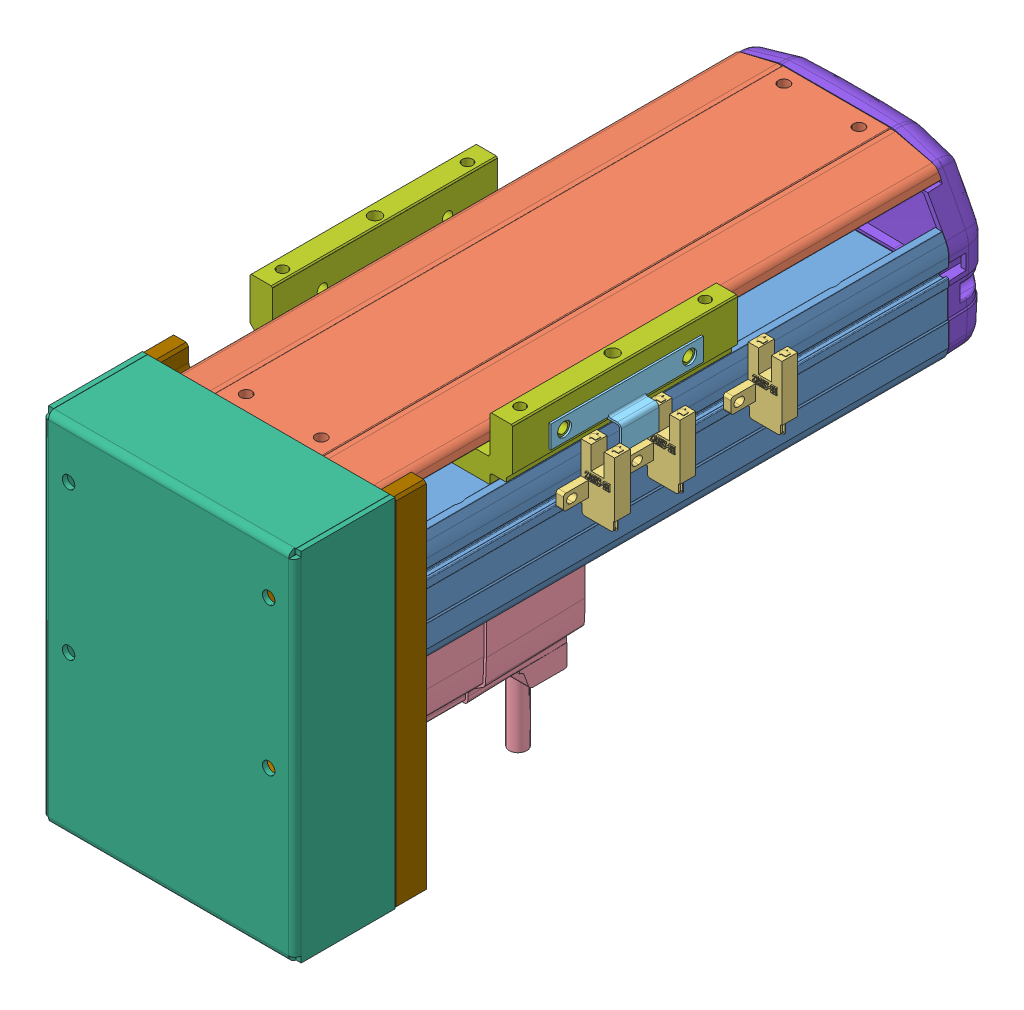
SolidWorks assembly S10-BM-100W, configuration 默认. Lengths in mm.
Overall size (117 164.58 282.34).
11 component instances, 9 part files, 37 mates.
Components (placement in the parent):
- CFS10-BR底座^CFS10-BM-100W-1: CFS10-BR底座^CFS10-BM-100W [默认] at origin size (102 43 221) (virtual)
- CFS10-BR上盖^CFS10-BM-100W-1: CFS10-BR上盖^CFS10-BM-100W [默认] at (0 59.5 119.5) size (83.88 8 227) (virtual)
-  EE-SX672 传感器^CFS10-BM-100W-1:  EE-SX672 传感器^CFS10-BM-100W [默认] at (57.75 34.1 92.3) x (1 0 0) z (0 0 -1) size (13.5 27.4 26.1) (virtual)
- M10^CFS10-BM-100W-1: M10^CFS10-BM-100W [默认] at (0 -40.88 167) x (-1 0 0) z (0 0 -1) size (42.1 79.78 121.76) (virtual)
- CFS10-GY外置感应钢片^CFS10-BM-100W-1: CFS10-GY外置感应钢片^CFS10-BM-100W [默认] at (52.9 60.5 143) size (6 19 61) (virtual)
-  EE-SX672 传感器^CFS10-BM-100W-2:  EE-SX672 传感器^CFS10-BM-100W [默认] at (57.75 34.1 133.1) x (1 0 0) z (0 0 -1) size (13.5 27.4 26.1) (virtual)
-  EE-SX672 传感器^CFS10-BM-100W-3:  EE-SX672 传感器^CFS10-BM-100W [默认] at (57.75 34.1 159.2) x (1 0 0) z (0 0 -1) size (13.5 27.4 26.1) (virtual)
- CFS10-BM盖子^CFS10-BM-100W-1: CFS10-BM盖子^CFS10-BM-100W [默认] at (0 -9.75 271) x (0 1 0) z (0 0 -1) size (142.51 101.01 40.01) (virtual)
- CFS10-BC滑座^CFS10-BM-100W-1: CFS10-BC滑座^CFS10-BM-100W [默认] at (-18.5 30.5 143) size (105 52.5 90) (virtual)
- CFS10端盖^CFS10-BC-100W1(中性）-1: CFS10端盖^CFS10-BC-100W1(中性） [Default] at (0.1 -0.919 432) size (104.96 63.3 21.34)
- 复件 电机板S10-BM-P38-T40^CFS10-BM-100W-1: 复件 电机板S10-BM-P38-T40^CFS10-BM-100W [Default] at (172.8992 -383.1572 151.741) size (102 142.5 12) (virtual)
Mates (geometry in assembly coordinates):
- 距离2: distance = 62.5 mm: plane of CFS10-BR上盖^CFS10-BM-100W-1 through (-21.3092 61.5 233) normal (0 1 0); plane of CFS10-BR底座^CFS10-BM-100W-1 through (0 -1 0) normal (0 -1 0)
- 重合31: coincident: plane of CFS10-BR底座^CFS10-BM-100W-1 through (0 0 0) normal (1 0 0); plane of CFS10-BR上盖^CFS10-BM-100W-1 through (0 59.5 119.5) normal (1 0 0)
- 距离3: distance = 66 mm: plane of CFS10-BC滑座^CFS10-BM-100W-1 through (-70.1396 65 72.2427) normal (0 1 0); plane of CFS10-BR底座^CFS10-BM-100W-1 through (0 -1 0) normal (0 -1 0)
- 距离5: distance = 1.5 mm: plane of CFS10-BC滑座^CFS10-BM-100W-1 through (52.5 45.0828 188) normal (1 0 0); plane of CFS10-BR底座^CFS10-BM-100W-1 through (51 3.0554 221) normal (1 0 0)
- 距离8: distance = 24 mm: plane of CFS10-BR底座^CFS10-BM-100W-1 through (0 -1 0) normal (0 -1 0); plane of  EE-SX672 传感器^CFS10-BM-100W-1 through (51 23 86) normal (0 -1 0)
- 重合67: coincident: plane of CFS10-BR底座^CFS10-BM-100W-1 through (51 24.0824 221) normal (1 0 0); plane of  EE-SX672 传感器^CFS10-BM-100W-1 through (51 45.2 86) normal (-1 0 0)
- 重合43: coincident: plane of CFS10-BC滑座^CFS10-BM-100W-1 through (52.5 45.0828 188) normal (1 0 0); plane of CFS10-GY外置感应钢片^CFS10-BM-100W-1 through (52.5 58.5 112.5) normal (-1 0 0)
- 同心16: concentric: cylinder of CFS10-BC滑座^CFS10-BM-100W-1 through (52.5 54 168) axis (1 0 0) radius 2.1; cylinder of ? through (52.5 54 173.8) axis (-1 0 0) radius 2.8
- 同心17: concentric: cylinder of CFS10-BC滑座^CFS10-BM-100W-1 through (52.5 54 118) axis (1 0 0) radius 2.1; cylinder of ? through (52.5 54 123.8) axis (-1 0 0) radius 2.8
- 重合51: coincident: plane of  EE-SX672 传感器^CFS10-BM-100W-1 through (51 45.2 86) normal (0 1 0); plane of  EE-SX672 传感器^CFS10-BM-100W-2 through (51 45.2 126.8) normal (0 1 0)
- 重合52: coincident: plane of  EE-SX672 传感器^CFS10-BM-100W-1 through (51 45.2 86) normal (0 1 0); plane of  EE-SX672 传感器^CFS10-BM-100W-3 through (51 45.2 152.9) normal (0 1 0)
- 平行2: parallel: plane of M10^CFS10-BM-100W-1 through (0 -60.88 167) normal (0 -1 0); plane of CFS10-BM盖子^CFS10-BM-100W-1 through (-48.5 -81 271) normal (0 -1 0)
- 重合64: coincident: plane of  EE-SX672 传感器^CFS10-BM-100W-2 through (54 26.2 143) normal (0 0 1); plane of  EE-SX672 传感器^CFS10-BM-100W-3 through (54 26.2 143) normal (0 0 -1)
- 重合65: coincident: plane of  EE-SX672 传感器^CFS10-BM-100W-2 through (51 45.2 126.8) normal (-1 0 0); plane of  EE-SX672 传感器^CFS10-BM-100W-3 through (51 45.2 152.9) normal (-1 0 0)
- 重合66: coincident: plane of  EE-SX672 传感器^CFS10-BM-100W-1 through (51 45.2 86) normal (-1 0 0); plane of  EE-SX672 传感器^CFS10-BM-100W-3 through (51 45.2 152.9) normal (-1 0 0)
- 重合69: coincident: plane of CFS10-BR底座^CFS10-BM-100W-1 through (0 0 0) normal (1 0 0); plane of assembly through (0 0 0) normal (1 0 0)
- 重合70: coincident: plane of CFS10-BR底座^CFS10-BM-100W-1 through (0 0 0) normal (0 1 0); plane of assembly through (0 0 0) normal (0 1 0)
- 重合71: coincident: plane of CFS10-BR底座^CFS10-BM-100W-1 through (0 0 0) normal (0 0 1); plane of assembly through (0 0 0) normal (0 0 1)
- 重合72: coincident: line of CFS10-BR底座^CFS10-BM-100W-1 through (49.0002 -24.5001 0) axis (0 1 0); line of CFS10端盖^CFS10-BC-100W1(中性）-1 through (69.5 -34.65 0) axis (0 1 0)
- 重合80: coincident: plane of CFS10-BR底座^CFS10-BM-100W-1 through (47.1 26.4495 221) normal (1 0 0); line of CFS10端盖^CFS10-BC-100W1(中性）-1 through (47.1 34.3616 4.2773) axis (0 -0.973655 0.228026)
- 重合81: coincident: plane of CFS10-BR上盖^CFS10-BM-100W-1 through (-39.9297 53.7 233) normal (0 0 1); plane of CFS10-BM盖子^CFS10-BM-100W-1 through (48 61.5 233) normal (0 0 -1)
- 宽度1: width: plane of CFS10-BM盖子^CFS10-BM-100W-1 through (50.5 -78.5 271) normal (1 0 0); plane of CFS10-BM盖子^CFS10-BM-100W-1 through (-50.5 59 271) normal (-1 0 0); plane of 复件 电机板S10-BM-P38-T40^CFS10-BM-100W-1 through (-51 61.5 233) normal (-1 0 0); plane of 复件 电机板S10-BM-P38-T40^CFS10-BM-100W-1 through (51 61.5 233) normal (1 0 0)
- 重合84: coincident: plane of CFS10-BM盖子^CFS10-BM-100W-1 through (48 61.5 233) normal (0 0 -1); plane of 复件 电机板S10-BM-P38-T40^CFS10-BM-100W-1 through (172.8992 -383.1572 233) normal (0 0 1)
- 重合85: coincident: plane of CFS10-BR底座^CFS10-BM-100W-1 through (-45.6042 41.8 221) normal (0 0 1); plane of 复件 电机板S10-BM-P38-T40^CFS10-BM-100W-1 through (172.8992 -383.1572 221) normal (0 0 -1)
- 重合86: coincident: plane of CFS10-BM盖子^CFS10-BM-100W-1 through (-48.5 -81 271) normal (0 -1 0); plane of 复件 电机板S10-BM-P38-T40^CFS10-BM-100W-1 through (-51 -81 233) normal (0 -1 0)
- 宽度2: width: plane of 复件 电机板S10-BM-P38-T40^CFS10-BM-100W-1 through (-51 61.5 233) normal (-1 0 0); plane of 复件 电机板S10-BM-P38-T40^CFS10-BM-100W-1 through (51 61.5 233) normal (1 0 0); plane of CFS10-BR底座^CFS10-BM-100W-1 through (50.5 12.5824 221) normal (1 0 0); plane of CFS10-BR底座^CFS10-BM-100W-1 through (-50.5 23.4167 221) normal (-1 0 0)
- 距离13: distance = 80 mm: plane of CFS10-BR底座^CFS10-BM-100W-1 through (0 -1 0) normal (0 -1 0); plane of 复件 电机板S10-BM-P38-T40^CFS10-BM-100W-1 through (-51 -81 233) normal (0 -1 0)
- 重合88: coincident: plane of M10^CFS10-BM-100W-1 through (-77.9984 -42.3778 223) normal (0 0 1); plane of 复件 电机板S10-BM-P38-T40^CFS10-BM-100W-1 through (172.8992 -383.1572 223) normal (0 0 -1)
- 宽度3: width: plane of CFS10-BM盖子^CFS10-BM-100W-1 through (50.5 -78.5 271) normal (1 0 0); plane of CFS10-BM盖子^CFS10-BM-100W-1 through (-50.5 59 271) normal (-1 0 0); plane of M10^CFS10-BM-100W-1 through (-20 -60.88 223) normal (-1 0 0); plane of M10^CFS10-BM-100W-1 through (20 -20.88 223) normal (1 0 0)
- 距离15: distance = 108 mm: plane of  EE-SX672 传感器^CFS10-BM-100W-3 through (64.5 23 159.2) normal (0 0 1); plane of CFS10-BM盖子^CFS10-BM-100W-1 through (48.5 -79 273) normal (0 0 1)
- 距离16: distance = 74 mm: plane of  EE-SX672 传感器^CFS10-BM-100W-1 through (64.5 23 86) normal (0 0 -1); plane of CFS10端盖^CFS10-BC-100W1(中性）-1 through (-43.0846 35.081 12) normal (0 0 1)
- 宽度6: width: plane of ? through (64.5 23 158.7) normal (0 0 -1); plane of ? through (64.5 23 138.9) normal (0 0 1); plane of ? through (53.3 49.5 156.3) normal (0 0 1); plane of ? through (53.3 49.5 141.3) normal (0 0 -1)
- 距离17: distance = 39.88 mm: cylinder of M10^CFS10-BM-100W-1 through (0 -40.88 248) axis (0 0 -1) radius 4; plane of CFS10-BR底座^CFS10-BM-100W-1 through (0 -1 0) normal (0 -1 0)
- 距离18: distance = 130 mm: plane of CFS10-BM盖子^CFS10-BM-100W-1 through (48.5 -79 273) normal (0 0 1); cylinder of CFS10-BC滑座^CFS10-BM-100W-1 through (47.5 53 143) axis (0 1 0) radius 2.5
- 同心18: concentric: cylinder of CFS10-GY外置感应钢片^CFS10-BM-100W-1 through (52.5 54 118) axis (-1 0 0) radius 2.8; cylinder of CFS10-BC滑座^CFS10-BM-100W-1 through (52.5 54 118) axis (1 0 0) radius 2.1
- 同心19: concentric: cylinder of CFS10-GY外置感应钢片^CFS10-BM-100W-1 through (52.5 54 168) axis (-1 0 0) radius 2.8; cylinder of CFS10-BC滑座^CFS10-BM-100W-1 through (52.5 54 168) axis (1 0 0) radius 2.1
- 宽度7: width: plane of  EE-SX672 传感器^CFS10-BM-100W-2 through (64.5 23 133.1) normal (0 0 1); plane of  EE-SX672 传感器^CFS10-BM-100W-3 through (64.5 23 152.9) normal (0 0 -1); plane of CFS10-GY外置感应钢片^CFS10-BM-100W-1 through (53.3 49.5 135.5) normal (0 0 -1); plane of CFS10-GY外置感应钢片^CFS10-BM-100W-1 through (53.3 49.5 150.5) normal (0 0 1)
